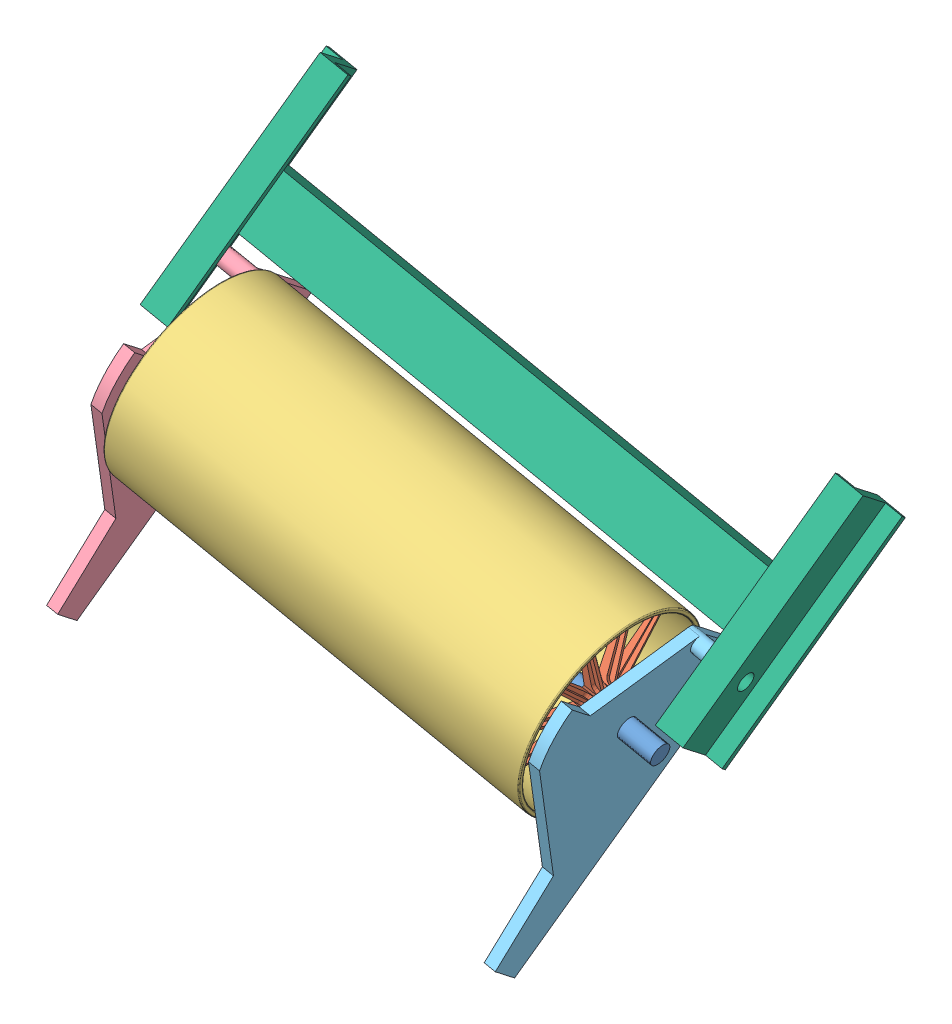
SolidWorks assembly doffer_frame_final - Copy, configuration Default. Lengths in mm.
Overall size (1106.4 932.96 729.79).
7 component instances, 6 part files, 14 mates.
Components (placement in the parent):
- Doffer Shaft-2: Doffer Shaft [Default] at (-268.4807 13986.1425 8078.4527) x (-0.971099 0.236856 0.029407) z (-0.222088 -0.941857 0.252154) size (875 35 35)
- support-2: support [Default] at (-659.3483 14081.4773 8090.2891) x (-0.235667 -0.932057 -0.275193) z (0.971099 -0.236856 -0.029407) size (312.12 307.38 70.5)
- support-3: support [Default] at (68.9764 13903.8349 8068.2337) x (-0.013639 -0.178079 0.983922) z (-0.971099 0.236856 0.029407) size (312.12 307.38 70.5)
- Doffer Cylinder-1: Doffer Cylinder [Default] at (-659.3483 14081.4773 8090.2891) x (-0.971099 0.236856 0.029407) z (-0.205722 -0.768176 -0.606287) size (750 331 331)
- Doffer_Frame-8: Doffer_Frame [Default] at (-674.0001 14091.7528 7863.7378) x (-0.160938 -0.740808 0.652152) z (-0.971099 0.236856 0.029407) size (531.95 337.74 70)
- Doffer_Frame2-4: Doffer_Frame2 [Default] at (93.1685 13904.6362 7840.5061) x (-0.160938 -0.740808 0.652152) z (-0.971099 0.236856 0.029407) size (522.5 337.74 70)
- intermediate_frame-1: intermediate_frame [Default] at (192.5398 14030.8847 7894.8011) x (0.971099 -0.236856 -0.029407) z (-0.160938 -0.740808 0.652152) size (1040 80 400)
Mates (geometry in assembly coordinates):
- Concentric1: concentric: cylinder of Doffer Shaft-2 through (-693.3368 14089.7672 8091.3184) axis (0.971099 -0.236856 -0.029407) radius 17.5; cylinder of support-2 through (-620.5043 14072.003 8089.1128) axis (-0.971099 0.236856 0.029407) radius 17.5
- Distance4: distance = 800 mm: plane of support-2 through (-620.5043 14072.003 8089.1128) normal (0.971099 -0.236856 -0.029407); plane of Doffer Shaft-2 through (156.3753 13882.5178 8065.587) normal (0.971099 -0.236856 -0.029407)
- Concentric4: concentric: cylinder of Doffer Shaft-2 through (-693.3368 14089.7672 8091.3184) axis (0.971099 -0.236856 -0.029407) radius 17.5; cylinder of support-3 through (30.1324 13913.3092 8069.41) axis (0.971099 -0.236856 -0.029407) radius 17.5
- Distance9: distance = 745 mm: plane of support-3 through (30.1324 13913.3092 8069.41) normal (-0.971099 0.236856 0.029407); plane of Doffer Shaft-2 through (-693.3368 14089.7672 8091.3184) normal (-0.971099 0.236856 0.029407)
- Concentric5: concentric: cylinder of Doffer Shaft-2 through (-693.3368 14089.7672 8091.3184) axis (0.971099 -0.236856 -0.029407) radius 17.5; cylinder of Doffer Cylinder-1 through (68.9764 13903.8349 8068.2337) axis (-0.971099 0.236856 0.029407) radius 157.5
- Width1: width: plane of support-3 through (68.9764 13903.8349 8068.2337) normal (0.971099 -0.236856 -0.029407); plane of support-2 through (-659.3483 14081.4773 8090.2891) normal (-0.971099 0.236856 0.029407); plane of Doffer Cylinder-1 through (-659.3483 14081.4773 8090.2891) normal (-0.971099 0.236856 0.029407); plane of Doffer Cylinder-1 through (68.9764 13903.8349 8068.2337) normal (0.971099 -0.236856 -0.029407)
- Concentric6: concentric: cylinder of Doffer Shaft-2 through (-693.3368 14089.7672 8091.3184) axis (0.971099 -0.236856 -0.029407) radius 17.5; cylinder of Doffer_Frame-8 through (-688.4813 14088.583 8091.1713) axis (0.971099 -0.236856 -0.029407) radius 17.5
- Concentric7: concentric: cylinder of Doffer Shaft-2 through (-693.3368 14089.7672 8091.3184) axis (0.971099 -0.236856 -0.029407) radius 17.5; cylinder of Doffer_Frame2-4 through (78.6873 13901.4664 8067.9396) axis (0.971099 -0.236856 -0.029407) radius 17.5
- Distance10: distance = 10 mm: plane of Doffer_Frame2-4 through (73.7465 13909.3733 7841.0942) normal (-0.971099 0.236856 0.029407); plane of Doffer Cylinder-1 through (68.9764 13903.8349 8068.2337) normal (0.971099 -0.236856 -0.029407)
- Distance11: distance = 10 mm: plane of Doffer_Frame-8 through (-674.0001 14091.7528 7863.7378) normal (0.971099 -0.236856 -0.029407); plane of Doffer Cylinder-1 through (-659.3483 14081.4773 8090.2891) normal (-0.971099 0.236856 0.029407)
- Coincident6: coincident: plane of Doffer_Frame2-4 through (73.7465 13909.3733 7841.0942) normal (-0.176251 -0.628571 -0.757518); plane of assembly through (2590.1564 9237.3612 11132.3332) normal (-0.176251 -0.628571 -0.757518)
- Concentric8: concentric: cylinder of Doffer_Frame-8 through (-671.5135 14172.1207 7978.6457) axis (0.971099 -0.236856 -0.029407) radius 15; cylinder of intermediate_frame-1 through (226.7535 13953.0284 7951.444) axis (-0.971099 0.236856 0.029407) radius 15
- Width2: width: plane of intermediate_frame-1 through (-739.7157 14258.2669 7923.032) normal (-0.971099 0.236856 0.029407); plane of intermediate_frame-1 through (211.9618 14026.1476 7894.213) normal (0.971099 -0.236856 -0.029407); plane of Doffer_Frame-8 through (-720.0685 14183.9635 7980.116) normal (-0.971099 0.236856 0.029407); plane of Doffer_Frame2-4 through (163.6321 13968.4241 7953.3555) normal (0.971099 -0.236856 -0.029407)
- Parallel2: parallel: plane of intermediate_frame-1 through (-714.5781 14381.2857 7762.301) normal (-0.176251 -0.628571 -0.757518); plane of assembly through (2590.1564 9237.3612 11132.3332) normal (-0.176251 -0.628571 -0.757518)
